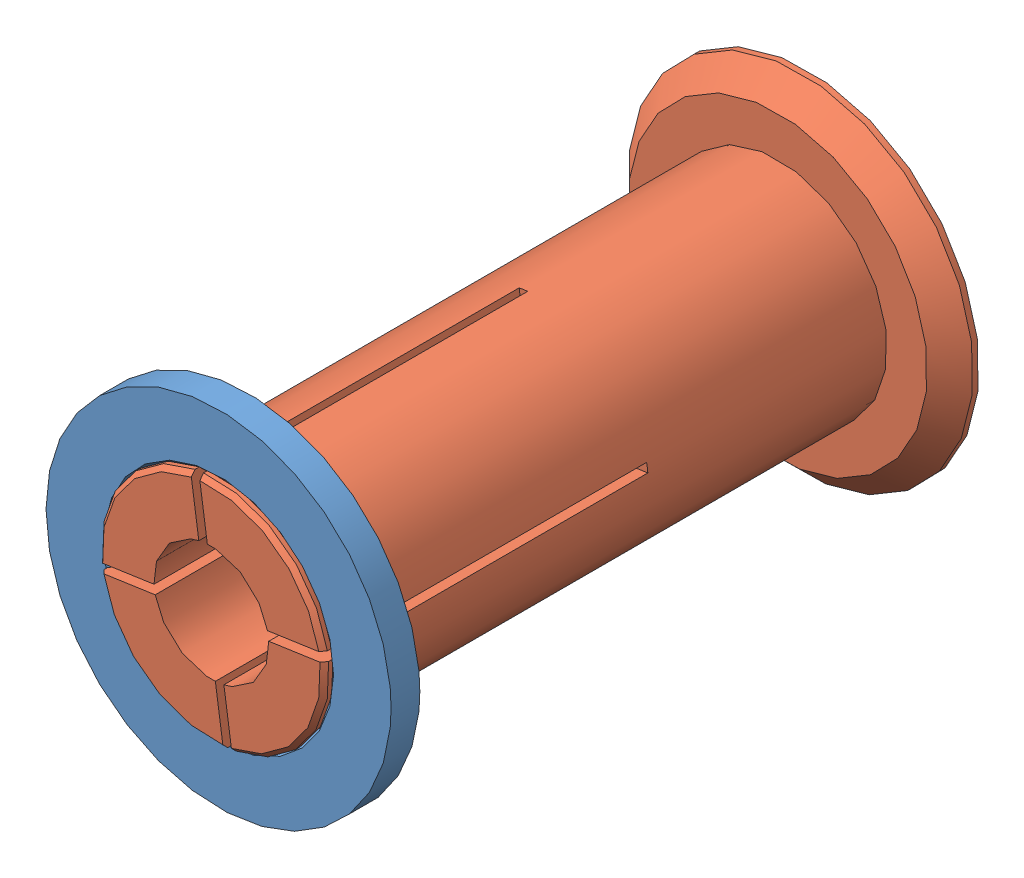
SolidWorks assembly 39-92-20-spool-adapter, configuration Default. Lengths in mm.
Overall size (68.03 68.03 103.5).
2 component instances, 2 part files, 2 mates.
Components (placement in the parent):
- 39-92-20-spool-adapter-female-1: 39-92-20-spool-adapter-female [Default] at (10.3753 28.3985 51.8774) size (60 60 5)
- 39-92-20-spool-adapter-male-1: 39-92-20-spool-adapter-male [Default] at (10.3753 28.3985 -40.3726) x (0.989529 0.144336 0) z (0 0 1) size (60 60 103.5)
Mates (geometry in assembly coordinates):
- Concentric1: concentric anti-aligned: cylinder of 39-92-20-spool-adapter-female-1 through (10.3753 28.3985 51.8774) axis (0 0 1) radius 19.25; cylinder of 39-92-20-spool-adapter-male-1 through (10.3753 28.3985 58.1274) axis (0 0 -1) radius 19
- Coincident1: coincident aligned: cone of 39-92-20-spool-adapter-female-1 through (10.3753 28.3985 56.8774) axis (0 0 -1); cone of 39-92-20-spool-adapter-male-1 through (10.3753 28.3985 56.6274) axis (0 0 -1)
